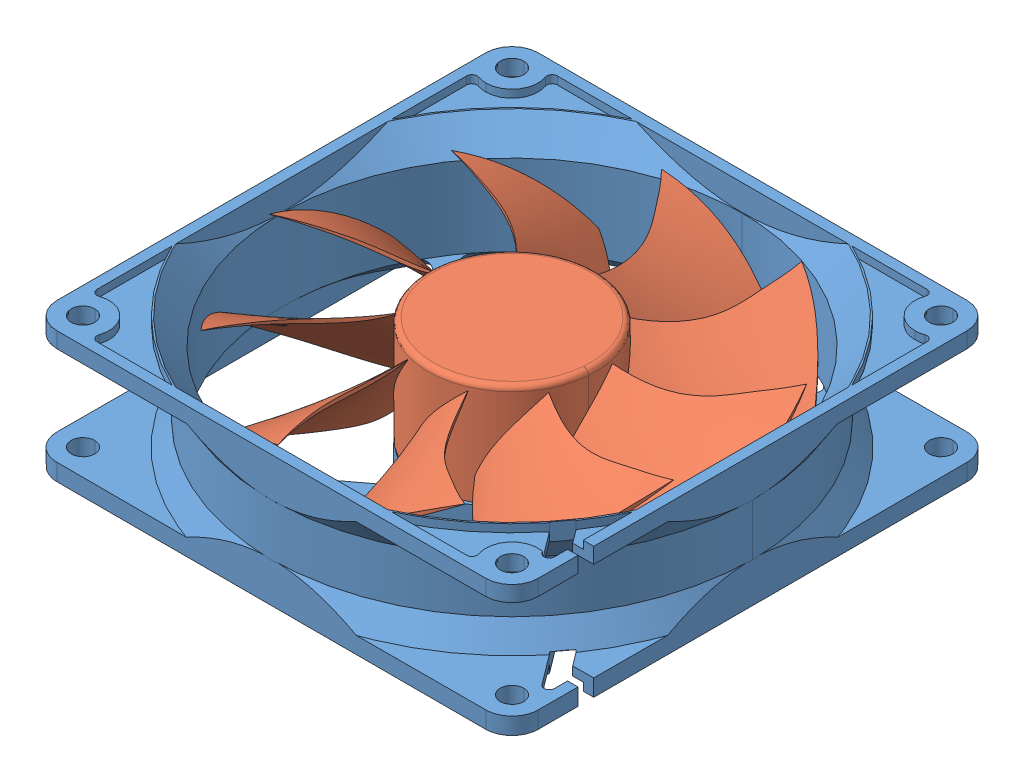
SolidWorks assembly F9, configuration Default. Lengths in mm.
Overall size (93.27 26.59 93.52).
3 component instances, 2 part files, 0 mates.
Components (placement in the parent):
- F9.STEP-1: F9.STEP [Default] at origin size (93.27 26.59 93.52)
  - F9 body.STEP-1: F9 body.STEP [Default] at (-78.1983 5.7094 50.7544) size (92.01 26.59 92.01)
  - F9 fan.STEP-1: F9 fan.STEP [Default] at (-74.2115 10.4094 -44.9134) x (-0.083202 0 0.996533) z (-0.996533 0 -0.083202) size (86.63 20 86.36)
